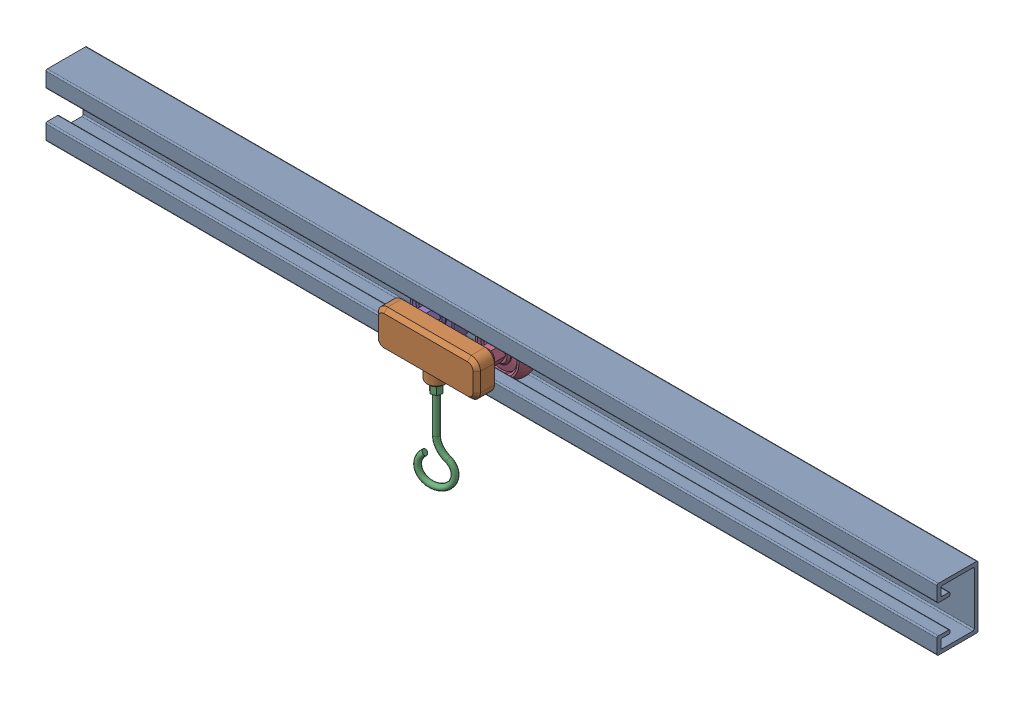
SolidWorks assembly 02_B_CSWA_Lvl9, configuration Default. Lengths in mm.
Overall size (1219.2 212.09 88.9).
5 component instances, 4 part files, 18 mates.
Components (placement in the parent):
- Base-Bracket-1: Base-Bracket [Default] at origin size (1219.2 85.09 55.88)
- Cart-1: Cart [Default] at (552.45 34.925 54.61) size (139.7 63.5 36.83)
- Hook-1: Hook [Default] at (552.45 -15.875 69.215) x (0.309017 0 0.951057) z (-0.951057 0 0.309017) size (12.7 160.65 48.26)
- Wheel-1: Wheel [Default] at (596.9 34.925 16.51) x (-1 0 0) z (0 0 1) size (69.85 69.85 64.77)
- Wheel-2: Wheel [Default] at (508 34.925 16.51) size (69.85 69.85 64.77)
Mates (geometry in assembly coordinates):
- Concentric1: concentric aligned: cylinder of Cart-1 through (88.9 34.925 77.47) axis (0 0 -1) radius 5.715; cylinder of Wheel-2 through (88.9 34.925 16.51) axis (0 0 -1) radius 5.08
- Coincident1: coincident aligned: circle of Cart-1; plane of Wheel-2 through (88.9 34.925 46.99) normal (0 0 1)
- Concentric2: concentric aligned: cylinder of Cart-1 through (177.8 34.925 77.47) axis (0 0 -1) radius 5.715; cylinder of Wheel-1 through (177.8 34.925 16.51) axis (0 0 -1) radius 5.08
- Concentric3: concentric aligned: cylinder of Cart-1 through (133.35 22.225 69.215) axis (0 -1 0) radius 5.08; cylinder of Hook-1 through (133.35 74.6934 69.215) axis (0 -1 0) radius 5.08
- Coincident3: coincident anti-aligned: plane of Cart-1 through (133.35 -3.175 69.215) normal (0 -1 0); plane of Hook-1 through (133.35 -3.175 69.215) normal (0 1 0)
- Parallel1: parallel aligned: plane of Cart-1 through (133.35 60.325 77.47) normal (0 1 0); plane of Wheel-1 through (183.6659 45.085 -14.4213) normal (0 1 0)
- Coincident4: coincident anti-aligned: plane of Cart-1 through (177.8 34.925 46.99) normal (0 0 -1); plane of Wheel-1 through (177.8 34.925 46.99) normal (0 0 1)
- Parallel2: parallel aligned: plane of Cart-1 through (133.35 60.325 77.47) normal (0 1 0); plane of Wheel-1 through (183.6659 45.085 -14.4213) normal (0 1 0)
- Parallel3: parallel aligned: plane of Cart-1 through (133.35 60.325 77.47) normal (0 1 0); plane of Wheel-2 through (94.7659 45.085 -14.4213) normal (0 1 0)
- Parallel4: parallel anti-aligned: plane of Base-Bracket-1 through (1219.2 57.15 45.72) normal (0 -1 0); plane of Wheel-1 through (183.6659 45.085 -14.4213) normal (0 1 0)
- Parallel5: parallel anti-aligned: plane of Base-Bracket-1 through (1219.2 57.15 45.72) normal (0 -1 0); plane of Wheel-2 through (94.7659 45.085 -14.4213) normal (0 1 0)
- Parallel6: parallel anti-aligned: plane of Base-Bracket-1 through (1219.2 74.93 50.8) normal (0 0 1); plane of Cart-1 through (133.35 34.925 54.61) normal (0 0 -1)
- Width1: width anti-aligned: plane of Base-Bracket-1 through (1219.2 17.78 33.02) normal (0 0 -1); plane of Wheel-1 through (1219.2 0 0) normal (0 0 1); plane of Base-Bracket-1 through (177.8 34.925 30.48) normal (0 0 1); plane of Wheel-1 through (177.8 34.925 2.54) normal (0 0 -1)
- Tangent1: tangent anti-aligned: plane of Base-Bracket-1 through (1219.2 0 0) normal (0 1 0); torus of Wheel-2
- Angle1: planar angle = 0.314159 rad aligned: plane of Hook-1 through (550.9255 -3.175 76.3871) normal (0.309017 0 0.951057); plane of Cart-1 through (552.45 34.925 83.82) normal (0 0 1)
- Distance3: distance = 482.6 mm aligned: plane of Cart-1 through (482.6 34.925 77.47) normal (-1 0 0); plane of Base-Bracket-1 through (0 0 0) normal (-1 0 0)
- Parallel8: parallel anti-aligned: plane of Base-Bracket-1 through (1219.2 0 50.8) normal (0 0 1); plane of Cart-1 through (133.35 34.925 54.61) normal (0 0 -1)
- Tangent2: tangent anti-aligned: plane of Base-Bracket-1 through (1219.2 0 0) normal (0 1 0); torus of Wheel-1
